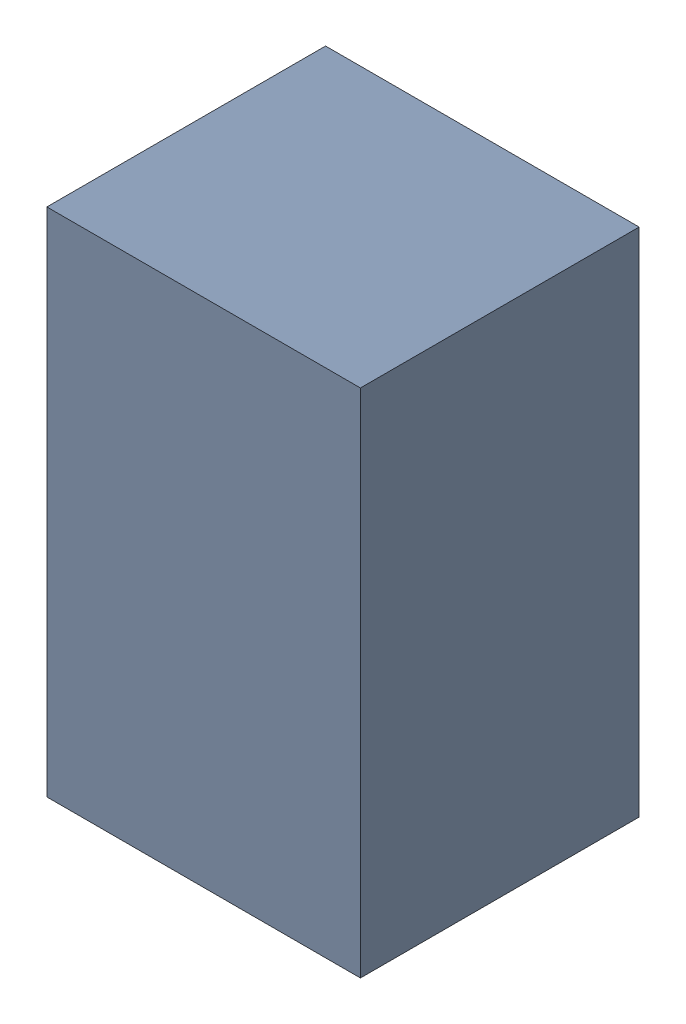
SolidWorks assembly C1, configuration Default. Lengths in mm.
Overall size (1.35 2.2 1.2).
2 component instances, 1 part files, 0 mates.
Components (placement in the parent):
- 407985568-1: 407985568 [Default] at (25.654 61.722 0.0127) size (1.35 2.2 1.2)
  - Extruded_3-1: Extruded_3 [Default] at origin size (1.35 2.2 1.2)
